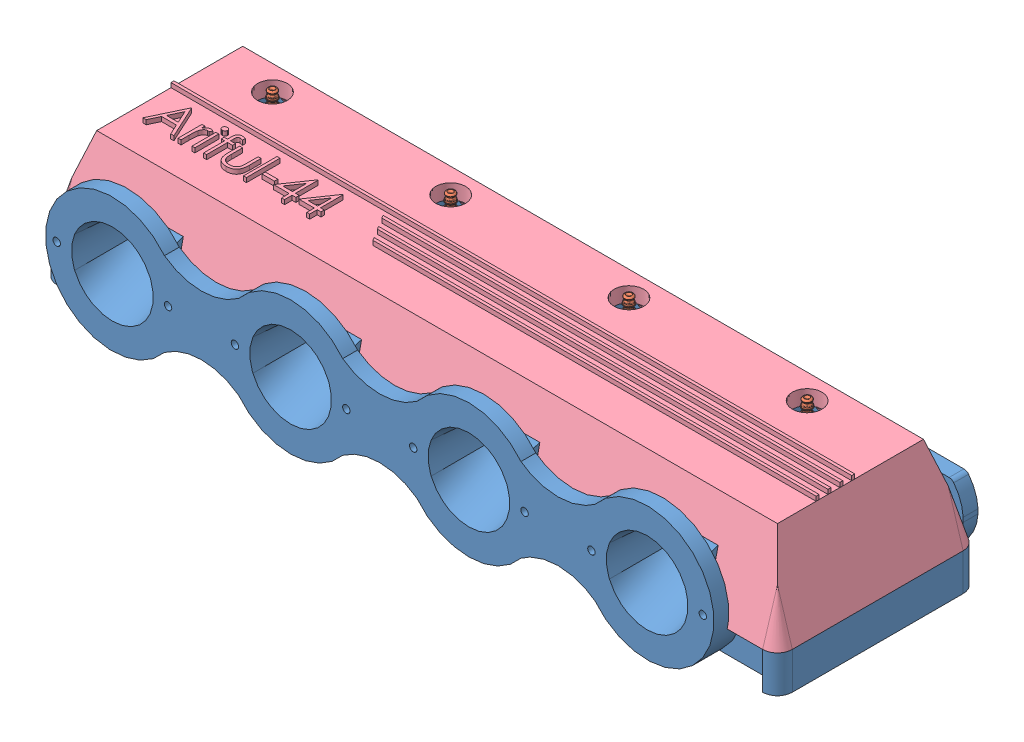
SolidWorks assembly HeadASSEM, configuration Default. Lengths in mm.
Overall size (495 98 155).
14 component instances, 4 part files, 31 mates.
Components (placement in the parent):
- head-1: head [Default] at (-68.8322 296.3763 369.1572) size (495 90 155)
- sparkplug-1: sparkplug [Default] at (38.6678 341.5148 336.6572) x (-0.837169 0 -0.546944) z (-0.546944 0 0.837169) size (16 84.49 18.48)
- sparkplug-2: sparkplug [Default] at (158.6678 341.5148 336.6572) x (-0.837169 0 -0.546944) z (-0.546944 0 0.837169) size (16 84.49 18.48)
- sparkplug-3: sparkplug [Default] at (278.6678 341.5148 336.6572) x (-0.837169 0 -0.546944) z (-0.546944 0 0.837169) size (16 84.49 18.48)
- sparkplug-4: sparkplug [Default] at (-81.3322 341.5148 336.6572) x (-0.837169 0 -0.546944) z (-0.546944 0 0.837169) size (16 84.49 18.48)
- campin-1: campin [Default] at (31.1678 376.3763 369.1572) x (-0.693491 0 -0.720466) z (0.720466 0 -0.693491) size (28 70 28)
- campin-2: campin [Default] at (-48.8322 376.3763 369.1572) x (-0.717846 0 0.696202) z (-0.696202 0 -0.717846) size (28 70 28)
- campin-3: campin [Default] at (151.1678 376.3763 369.1572) x (0.967975 0 -0.251048) z (0.251048 0 0.967975) size (28 70 28)
- campin-4: campin [Default] at (71.1678 376.3763 369.1572) x (-0.768196 0 0.640214) z (-0.640214 0 -0.768196) size (28 70 28)
- campin-6: campin [Default] at (-88.8322 376.3763 369.1572) x (0.884294 0 0.46693) z (-0.46693 0 0.884294) size (28 70 28)
- campin-5: campin [Default] at (191.1678 376.3763 369.1572) x (0.919682 0 -0.392664) z (0.392664 0 0.919682) size (28 70 28)
- campin-7: campin [Default] at (271.1678 376.3763 369.1572) x (0.288066 0 0.95761) z (-0.95761 0 0.288066) size (28 70 28)
- campin-8: campin [Default] at (311.1678 376.3763 369.1572) x (0 0 1) z (-1 0 0) size (28 70 28)
- cover-2: cover [Default] at (49.7609 309.3868 195.7023) size (495 63 135)
Mates (geometry in assembly coordinates):
- Concentric1: concentric anti-aligned: cylinder of head-1 through (-81.3322 371.3763 336.6572) axis (0 -1 0) radius 10; cylinder of sparkplug-4 through (-81.3322 327.5148 336.6572) axis (0 1 0) radius 8
- Concentric2: concentric anti-aligned: cylinder of head-1 through (38.6678 371.3763 336.6572) axis (0 -1 0) radius 10; cylinder of sparkplug-1 through (38.6678 327.5148 336.6572) axis (0 1 0) radius 8
- Concentric3: concentric aligned: cylinder of head-1 through (158.6678 371.3763 336.6572) axis (0 -1 0) radius 10; circle of sparkplug-2
- Concentric4: concentric anti-aligned: cylinder of head-1 through (278.6678 371.3763 336.6572) axis (0 -1 0) radius 10; cylinder of sparkplug-3 through (278.6678 327.5148 336.6572) axis (0 1 0) radius 8
- Coincident1: coincident aligned: cone of head-1 through (-81.3322 322.3763 336.6572) axis (0 -1 0); cone of sparkplug-4 through (-81.3322 322.8763 336.6572) axis (0 -1 0)
- Coincident2: coincident aligned: cone of head-1 through (38.6678 322.3763 336.6572) axis (0 -1 0); cone of sparkplug-1 through (38.6678 322.8763 336.6572) axis (0 -1 0)
- Coincident3: coincident aligned: cone of head-1 through (158.6678 322.3763 336.6572) axis (0 -1 0); cone of sparkplug-2 through (158.6678 322.8763 336.6572) axis (0 -1 0)
- Coincident4: coincident aligned: cone of head-1 through (278.6678 322.3763 336.6572) axis (0 -1 0); cone of sparkplug-3 through (278.6678 322.8763 336.6572) axis (0 -1 0)
- Concentric5: concentric aligned: cylinder of head-1 through (311.1678 333.4628 369.1572) axis (0 1 0) radius 4; cylinder of campin-8 through (311.1678 376.3763 369.1572) axis (0 1 0) radius 4
- Concentric6: concentric aligned: cylinder of head-1 through (271.1678 326.3763 369.1572) axis (0 1 0) radius 4; cylinder of campin-7 through (271.1678 376.3763 369.1572) axis (0 1 0) radius 4
- Concentric7: concentric aligned: cylinder of head-1 through (191.1678 333.4628 369.1572) axis (0 1 0) radius 4; cylinder of campin-5 through (191.1678 376.3763 369.1572) axis (0 1 0) radius 4
- Concentric8: concentric aligned: cylinder of head-1 through (151.1678 326.3763 369.1572) axis (0 1 0) radius 4; cylinder of campin-3 through (151.1678 376.3763 369.1572) axis (0 1 0) radius 4
- Concentric9: concentric aligned: cylinder of head-1 through (71.1678 333.4628 369.1572) axis (0 1 0) radius 4; cylinder of campin-4 through (71.1678 376.3763 369.1572) axis (0 1 0) radius 4
- Concentric10: concentric aligned: cylinder of head-1 through (31.1678 326.3763 369.1572) axis (0 1 0) radius 4; cylinder of campin-1 through (31.1678 376.3763 369.1572) axis (0 1 0) radius 4
- Concentric11: concentric aligned: cylinder of head-1 through (-88.8322 326.3763 369.1572) axis (0 1 0) radius 4; cylinder of campin-6 through (-88.8322 376.3763 369.1572) axis (0 1 0) radius 4
- Concentric12: concentric aligned: cylinder of head-1 through (-48.8322 333.4628 369.1572) axis (0 1 0) radius 4; cylinder of campin-2 through (-48.8322 376.3763 369.1572) axis (0 1 0) radius 4
- Concentric15: concentric anti-aligned: cylinder of campin-8 through (325.1678 372.3763 369.1572) axis (-1 0 0) radius 1.5; cylinder of ? through (306.1678 372.3763 369.1572) axis (1 0 0) radius 1
- Distance4: distance = 0.25 mm: plane of ? through (308.1678 375.3763 350.1572) normal (1 0 0); plane of campin-8 through (308.4178 376.3763 355.1572) normal (-1 0 0)
- Angle1: planar angle = 1.570796 rad: cylinder of ? through (311.1678 372.3763 362.1572) axis (0 0 -1) radius 3; cylinder of campin-8 through (311.1678 376.3763 369.1572) axis (0 1 0) radius 4
- Parallel7: parallel aligned: line of campin-8 through (313.9178 368.3763 366.2524) axis (0 0 1); line of head-1 through (358.6678 321.3763 311.6572) axis (0 0 1)
- Concentric17: concentric aligned: cylinder of campin-7 through (284.5743 372.3763 365.1242) axis (-0.95761 0 0.288066) radius 1.5; cylinder of ? through (275.3654 372.3763 366.4405) axis (-0.839515 0 0.543337) radius 1
- Distance5: distance = 0.25 mm: plane of ? through (258.3258 369.3763 354.8364) normal (0.839515 0 -0.543337); plane of campin-7 through (264.5014 376.3763 356.5428) normal (-0.95761 0 0.288066)
- Angle2: planar angle = 1.570796 rad aligned: cylinder of campin-7 through (271.1678 376.3763 369.1572) axis (0 1 0) radius 4; cylinder of ? through (267.3644 372.3763 363.2806) axis (-0.543337 0 -0.839515) radius 3
- Coincident5: coincident aligned: plane of head-1 through (291.1678 306.3763 369.1572) normal (0 -1 0); plane of campin-8 through (311.1678 306.3763 369.1572) normal (0 -1 0)
- Coincident6: coincident aligned: plane of head-1 through (291.1678 306.3763 369.1572) normal (0 -1 0); plane of campin-7 through (271.1678 306.3763 369.1572) normal (0 -1 0)
- Coincident7: coincident aligned: plane of head-1 through (171.1678 306.3763 369.1572) normal (0 -1 0); plane of campin-5 through (191.1678 306.3763 369.1572) normal (0 -1 0)
- Coincident8: coincident aligned: plane of head-1 through (171.1678 306.3763 369.1572) normal (0 -1 0); plane of campin-3 through (151.1678 306.3763 369.1572) normal (0 -1 0)
- Coincident9: coincident aligned: plane of head-1 through (51.1678 306.3763 369.1572) normal (0 -1 0); plane of campin-4 through (71.1678 306.3763 369.1572) normal (0 -1 0)
- Coincident10: coincident aligned: plane of head-1 through (51.1678 306.3763 369.1572) normal (0 -1 0); plane of campin-1 through (31.1678 306.3763 369.1572) normal (0 -1 0)
- Coincident11: coincident aligned: plane of head-1 through (-68.8322 306.3763 369.1572) normal (0 -1 0); plane of campin-2 through (-48.8322 306.3763 369.1572) normal (0 -1 0)
- Coincident12: coincident aligned: plane of head-1 through (-68.8322 306.3763 369.1572) normal (0 -1 0); plane of campin-6 through (-88.8322 306.3763 369.1572) normal (0 -1 0)
